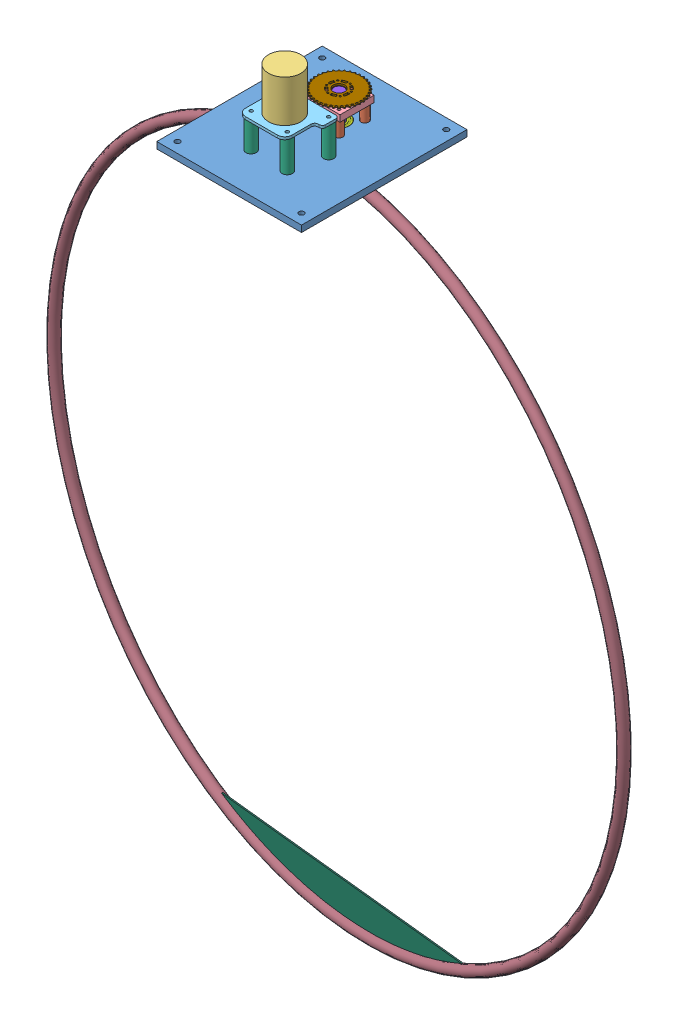
SolidWorks assembly Assem1, configuration Default. Lengths in mm.
Overall size (1611.39 1895.35 406.4).
23 component instances, 15 part files, 44 mates.
Components (placement in the parent):
- TopPlate-1: TopPlate [Default] at (75.4575 227.473 341.7213) size (355.6 15.88 406.4)
- Spacer1.5in-1: Spacer1.5in [Default] at (43.7075 243.348 243.2963) size (19.05 38.1 19.05)
- Almpflow F30-400-1: Almpflow F30-400 [Default] at (75.4575 429.022 408.3963) x (-0.682064 0 -0.731293) z (-0.731293 0 0.682064) size (79.5 150.11 79.5)
- Spacer1.5in-2: Spacer1.5in [Default] at (43.7075 243.348 306.7963) size (19.05 38.1 19.05)
- Spacer1.5in-3: Spacer1.5in [Default] at (107.2075 243.348 306.7963) size (19.05 38.1 19.05)
- Spacer1.5in-4: Spacer1.5in [Default] at (107.2075 243.348 243.2963) size (19.05 38.1 19.05)
- Ring Bearing Support-1: Ring Bearing Support [Default] at (75.4575 281.448 275.0463) x (1 0 0) z (0 1 0) size (88.9 83.82 15.88)
- MotMountPlate-1: MotMountPlate [Default] at (75.4575 319.548 408.3963) size (152.4 6.35 114.3)
- Spacer3.25-1: Spacer3.25 [Default] at (11.9575 243.348 363.9463) x (0.99965 0 0.026455) z (-0.026455 0 0.99965) size (25.4 76.2 25.4)
- Spacer3.25-2: Spacer3.25 [Default] at (119.9075 243.348 446.4963) x (0.966539 0 0.256519) z (-0.256519 0 0.966539) size (25.4 76.2 25.4)
- Spacer3.25-3: Spacer3.25 [Default] at (138.9575 243.348 363.9463) size (25.4 76.2 25.4)
- Spacer3.25-4: Spacer3.25 [Default] at (31.0075 243.348 446.4963) size (25.4 76.2 25.4)
- 60355K708 .75 Bearing-1: 60355K708 .75 Bearing [60355K708] at (75.4575 290.973 275.0463) x (1 0 0) z (0 -1 0) size (50.8 50.8 12.7)
- 60355K708 .75 Bearing-2: 60355K708 .75 Bearing [60355K708] at (75.4575 236.998 275.0463) x (1 0 0) z (0 -1 0) size (50.8 50.8 12.7)
- 1inch Shaft-1: 1inch Shaft [Default] at (75.4575 153.813 275.0463) x (-0.993473 0 -0.114063) z (0.114063 0 -0.993473) size (25.4 152.4 25.4)
- 36T Sprocket-1: 36T Sprocket [Default] at (75.4575 308.3593 275.0463) x (-0.342155 0 -0.939644) z (0 1 0) size (114.26 114.26 4.29)
- 12T Sprocket-1: 12T Sprocket [Default] at (75.4575 308.3593 408.3963) x (0.921307 0 -0.388837) z (0 -1 0) size (40.29 40.29 10.67)
- Hub-1: Hub [Default] at (75.4575 306.213 275.0463) x (-0.984833 0 -0.173507) z (0 -1 0) size (63.5 63.5 8.89)
- 2.75 Bolt 91251A594-1: 2.75 Bolt 91251A594 [91251A594] at (43.7075 306.213 243.2963) x (1 0 0) z (0 1 0) size (11.91 11.91 78.71)
- Assem2-1: Assem2 [Default] at (75.4575 -1466.326 275.0463) x (-0.993473 0 -0.114063) z (0.114063 0 -0.993473) size (1617.6 1655.7 38.1)
  - Ring-1: Ring [Default] at (0 808.7995 0) x (0 0 -1) z (-1 0 0) size (25.4 1617.6 1617.6)
  - SupportBlock-1: SupportBlock [Default] at (-38.1 1630.299 0) x (0 0 -1) z (1 0 0) size (38.1 51.94 76.2)
  - Elec Board-1: Elec Board [Default] at (-344.2695 105.9652 -1.6002) x (0.99992 -0.012661 0) z (0 0 1) size (670.56 76.2 3.2)
Mates (geometry in assembly coordinates):
- Concentric1: concentric anti-aligned: cylinder of TopPlate-1 through (43.7075 227.473 243.2963) axis (0 1 0) radius 4.064; cylinder of Spacer1.5in-1 through (43.7075 281.448 243.2963) axis (0 -1 0) radius 9.525
- Coincident1: coincident anti-aligned: plane of TopPlate-1 through (75.4575 243.348 341.7213) normal (0 1 0); plane of Spacer1.5in-1 through (43.7075 243.348 243.2963) normal (0 -1 0)
- Concentric2: concentric anti-aligned: cylinder of TopPlate-1 through (43.7075 227.473 306.7963) axis (0 1 0) radius 4.064; cylinder of Spacer1.5in-2 through (43.7075 281.448 306.7963) axis (0 -1 0) radius 9.525
- Concentric3: concentric anti-aligned: circle of TopPlate-1; cylinder of Spacer1.5in-3 through (107.2075 281.448 306.7963) axis (0 -1 0) radius 9.525
- Concentric4: concentric anti-aligned: circle of TopPlate-1; cylinder of Spacer1.5in-4 through (107.2075 281.448 243.2963) axis (0 -1 0) radius 9.525
- Coincident2: coincident anti-aligned: plane of TopPlate-1 through (75.4575 243.348 341.7213) normal (0 1 0); plane of Spacer1.5in-4 through (107.2075 243.348 243.2963) normal (0 -1 0)
- Coincident3: coincident anti-aligned: plane of TopPlate-1 through (75.4575 243.348 341.7213) normal (0 1 0); plane of Spacer1.5in-3 through (107.2075 243.348 306.7963) normal (0 -1 0)
- Coincident4: coincident anti-aligned: plane of TopPlate-1 through (75.4575 243.348 341.7213) normal (0 1 0); plane of Spacer1.5in-2 through (43.7075 243.348 306.7963) normal (0 -1 0)
- Coincident5: coincident anti-aligned: plane of Spacer1.5in-1 through (43.7075 281.448 243.2963) normal (0 1 0); plane of Ring Bearing Support-1 through (75.4575 281.448 275.0463) normal (0 -1 0)
- Concentric6: concentric anti-aligned: cylinder of Spacer1.5in-4 through (107.2075 281.448 243.2963) axis (0 -1 0) radius 4.064; cylinder of Ring Bearing Support-1 through (107.2075 281.448 243.2963) axis (0 1 0) radius 3.2639
- Concentric7: concentric anti-aligned: cylinder of Spacer1.5in-1 through (43.7075 281.448 243.2963) axis (0 -1 0) radius 4.064; cylinder of Ring Bearing Support-1 through (43.7075 281.448 243.2963) axis (0 1 0) radius 3.2639
- Concentric8: concentric aligned: cylinder of TopPlate-1 through (138.9575 227.473 363.9463) axis (0 1 0) radius 4.064; cylinder of MotMountPlate-1 through (138.9575 319.548 363.9463) axis (0 1 0) radius 4.064
- Concentric10: concentric aligned: cylinder of Almpflow F30-400-1 through (75.4575 278.908 408.3963) axis (0 1 0) radius 6.35; cylinder of MotMountPlate-1 through (75.4575 319.548 408.3963) axis (0 1 0) radius 17.4625
- Coincident6: coincident anti-aligned: plane of Almpflow F30-400-1 through (75.4575 325.898 408.3963) normal (0 -1 0); plane of MotMountPlate-1 through (75.4575 325.898 408.3963) normal (0 1 0)
- Concentric11: concentric anti-aligned: circle of MotMountPlate-1; cylinder of Spacer3.25-1 through (11.9575 319.548 363.9463) axis (0 -1 0) radius 12.7
- Coincident7: coincident anti-aligned: plane of MotMountPlate-1 through (75.4575 319.548 408.3963) normal (0 -1 0); circle of Spacer3.25-1
- Coincident8: coincident aligned: plane of TopPlate-1 through (75.4575 243.348 341.7213) normal (0 1 0); circle of Spacer3.25-1
- Concentric12: concentric anti-aligned: circle of MotMountPlate-1; cylinder of Spacer3.25-2 through (119.9075 319.548 446.4963) axis (0 -1 0) radius 12.7
- Coincident9: coincident anti-aligned: plane of MotMountPlate-1 through (75.4575 319.548 408.3963) normal (0 -1 0); plane of Spacer3.25-2 through (119.9075 319.548 446.4963) normal (0 1 0)
- Coincident10: coincident anti-aligned: plane of MotMountPlate-1 through (75.4575 319.548 408.3963) normal (0 -1 0); plane of Spacer3.25-4 through (31.0075 319.548 446.4963) normal (0 1 0)
- Concentric13: concentric anti-aligned: cylinder of MotMountPlate-1 through (31.0075 319.548 446.4963) axis (0 1 0) radius 4.064; cylinder of Spacer3.25-4 through (31.0075 319.548 446.4963) axis (0 -1 0) radius 12.7
- Coincident11: coincident anti-aligned: plane of MotMountPlate-1 through (75.4575 319.548 408.3963) normal (0 -1 0); plane of Spacer3.25-3 through (138.9575 319.548 363.9463) normal (0 1 0)
- Concentric14: concentric anti-aligned: cylinder of MotMountPlate-1 through (138.9575 319.548 363.9463) axis (0 1 0) radius 4.064; cylinder of Spacer3.25-3 through (138.9575 319.548 363.9463) axis (0 -1 0) radius 12.7
- Coincident12: coincident anti-aligned: circle of TopPlate-1; cylinder of 60355K708 .75 Bearing-2 through (75.4575 230.648 275.0463) axis (0 -1 0) radius 25.4
- Coincident13: coincident anti-aligned: circle of TopPlate-1; plane of 60355K708 .75 Bearing-2 through (75.4575 230.648 299.8113) normal (0 -1 0)
- Concentric15: concentric anti-aligned: cylinder of Ring Bearing Support-1 through (75.4575 284.623 275.0463) axis (0 1 0) radius 25.4; cylinder of 60355K708 .75 Bearing-1 through (75.4575 284.623 275.0463) axis (0 -1 0) radius 25.4
- Coincident14: coincident anti-aligned: plane of Ring Bearing Support-1 through (75.4575 284.623 275.0463) normal (0 1 0); plane of 60355K708 .75 Bearing-1 through (75.4575 284.623 299.8113) normal (0 -1 0)
- Concentric16: concentric aligned: cylinder of 60355K708 .75 Bearing-1 through (75.4575 284.623 275.0463) axis (0 -1 0) radius 12.7; cylinder of 1inch Shaft-1 through (75.4575 306.213 275.0463) axis (0 -1 0) radius 12.7
- Concentric19: concentric aligned: cylinder of Almpflow F30-400-1 through (75.4575 278.908 408.3963) axis (0 1 0) radius 6.35; cylinder of 12T Sprocket-1 through (75.4575 299.8313 408.3963) axis (0 1 0) radius 12.7
- Concentric20: concentric anti-aligned: cylinder of 1inch Shaft-1 through (75.4575 306.213 275.0463) axis (0 -1 0) radius 12.7; cylinder of 36T Sprocket-1 through (75.4575 308.3593 275.0463) axis (0 1 0) radius 14.3
- Coincident16: coincident aligned: plane of 36T Sprocket-1 through (75.4575 310.5056 275.0463) normal (0 1 0); plane of 12T Sprocket-1 through (81.628 310.5056 423.0165) normal (0 1 0)
- Parallel1: parallel aligned: plane of TopPlate-1 through (-102.3425 243.348 544.9213) normal (0 0 1); plane of MotMountPlate-1 through (18.3075 325.898 465.5463) normal (0 0 1)
- Concentric22: concentric aligned: cylinder of 1inch Shaft-1 through (75.4575 306.213 275.0463) axis (0 -1 0) radius 12.7; cylinder of Hub-1 through (75.4575 306.213 275.0463) axis (0 -1 0) radius 12.7
- Concentric23: concentric aligned: circle of 36T Sprocket-1; circle of Hub-1
- Concentric24: concentric aligned: circle of 36T Sprocket-1; circle of Hub-1
- Coincident17: coincident aligned: plane of 1inch Shaft-1 through (75.4575 306.213 275.0463) normal (0 1 0); plane of Hub-1 through (75.4575 306.213 275.0463) normal (0 1 0)
- Coincident18: coincident anti-aligned: plane of 36T Sprocket-1 through (26.0975 306.213 293.0199) normal (0 -1 0); plane of Hub-1 through (75.4575 306.213 275.0463) normal (0 1 0)
- Coincident19: coincident anti-aligned: plane of 60355K708 .75 Bearing-1 through (75.4575 297.323 288.3813) normal (0 1 0); plane of Hub-1 through (75.4575 297.323 275.0463) normal (0 -1 0)
- Coincident20: coincident aligned: plane of 36T Sprocket-1 through (75.4575 310.5056 275.0463) normal (0 1 0); plane of 12T Sprocket-1 through (81.628 310.5056 423.0165) normal (0 1 0)
- Concentric27: concentric anti-aligned: cylinder of Spacer1.5in-1 through (43.7075 281.448 243.2963) axis (0 -1 0) radius 9.525; cylinder of 2.75 Bolt 91251A594-1 through (43.7075 236.363 243.2963) axis (0 1 0) radius 3.9688
- Coincident23: coincident anti-aligned: plane of TopPlate-1 through (43.7075 236.363 243.2963) normal (0 -1 0); circle of 2.75 Bolt 91251A594-1
- Concentric28: concentric anti-aligned: cylinder of 1inch Shaft-1 through (75.4575 306.213 275.0463) axis (0 -1 0) radius 12.7; cylinder of Assem2-1/SupportBlock-1 through (75.4575 138.573 275.0463) axis (0 1 0) radius 12.7635
- Concentric29: concentric anti-aligned: cylinder of 1inch Shaft-1 through (74.0089 162.703 287.6635) axis (0.114063 0 -0.993473) radius 3.175; cylinder of Assem2-1/SupportBlock-1 through (77.6304 162.703 256.1207) axis (-0.114063 0 0.993473) radius 3.175
- Lock1: lock: unknown of 1inch Shaft-1; unknown of Hub-1
